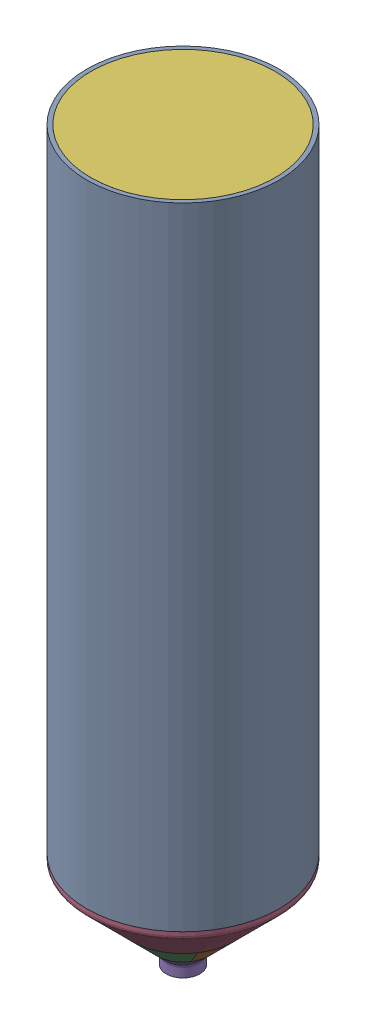
SolidWorks assembly Hopper_Tank_Assembly, configuration Default. Lengths in mm.
Overall size (210.94 576.2 210.94).
6 component instances, 6 part files, 5 mates.
Components (placement in the parent):
- Hopper_Tank_Tube-1: Hopper_Tank_Tube [Default] at origin size (152.4 500 152.4)
- Hopper_Tank_Funnel-1: Hopper_Tank_Funnel [Default] x (-0.837169 0 -0.546944) z (-0.546944 0 0.837169) size (152.4 76.2 152.4)
- Hopper_Tank_End_Cap-1: Hopper_Tank_End_Cap [Default] at (0 500 0) x (-0.837169 0 -0.546944) z (-0.546944 0 0.837169) size (145.9 10 145.9) (hidden)
- Hopper_Tank_Bottom_Cap-1: Hopper_Tank_Bottom_Cap [Default] at (0 -76.2 0) size (20 10 20)
- Hopper_Tank_Plunger_Head-1: Hopper_Tank_Plunger_Head [Default] at (0 394.7592 0) x (0.99942 0 -0.034068) z (0.034068 0 0.99942) size (146.8 10.84 146.8)
- Hopper_Tank_Head_Connector-1: Hopper_Tank_Head_Connector [Default] at (0 394.7794 0) x (0.239409 0 -0.970919) z (0.970919 0 0.239409) size (25 30.28 25)
Mates (geometry in assembly coordinates):
- Coincident3: coincident anti-aligned: circle of Hopper_Tank_Tube-1; circle of Hopper_Tank_Funnel-1
- Coincident4: coincident anti-aligned: circle of Hopper_Tank_Tube-1; circle of Hopper_Tank_End_Cap-1
- Coincident5: coincident aligned: circle of Hopper_Tank_Funnel-1; circle of Hopper_Tank_Bottom_Cap-1
- Concentric1: concentric anti-aligned: circle of Hopper_Tank_Tube-1; circle of Hopper_Tank_Plunger_Head-1
- Screw1: screw = 2.5 mm anti-aligned: circle of Hopper_Tank_Plunger_Head-1; cylinder of Hopper_Tank_Head_Connector-1 through (0 424.7794 0) axis (0 -1 0) radius 12.5
